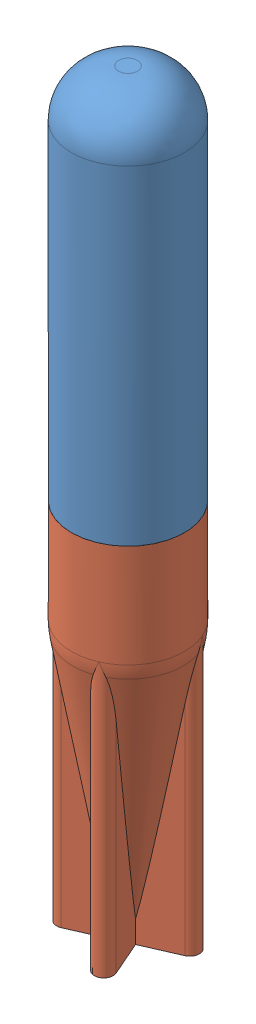
SolidWorks assembly Fin torpedo, configuration Default. Lengths in mm.
Overall size (15.8 80 15.8).
2 component instances, 2 part files, 2 mates.
Components (placement in the parent):
- MS-P-0052- Flywheel Torpedo Body-1: MS-P-0052- Flywheel Torpedo Body [Default] at (13.4209 3.732 29.5587) size (12 40 12)
- MS-P-0051- Flywheel Torpedo Fins-1: MS-P-0051- Flywheel Torpedo Fins [Default] at (13.4209 11.732 29.5587) x (-0.916326 0 0.400432) z (0.400432 0 0.916326) size (12 48 12)
Mates (geometry in assembly coordinates):
- Concentric1: concentric: cylinder of Fin torpedo body v1-1 through (13.4209 43.732 29.5587) axis (0 -1 0) radius 5; cylinder of fin torpedo cap - fins-1 through (13.4209 -54.7247 29.5587) axis (0 1 0) radius 6
- Coincident1: coincident anti-aligned: plane of Fin torpedo body v1-1 through (13.4209 3.732 29.5587) normal (0 -1 0); plane of fin torpedo cap - fins-1 through (13.4209 3.732 29.5587) normal (0 1 0)
